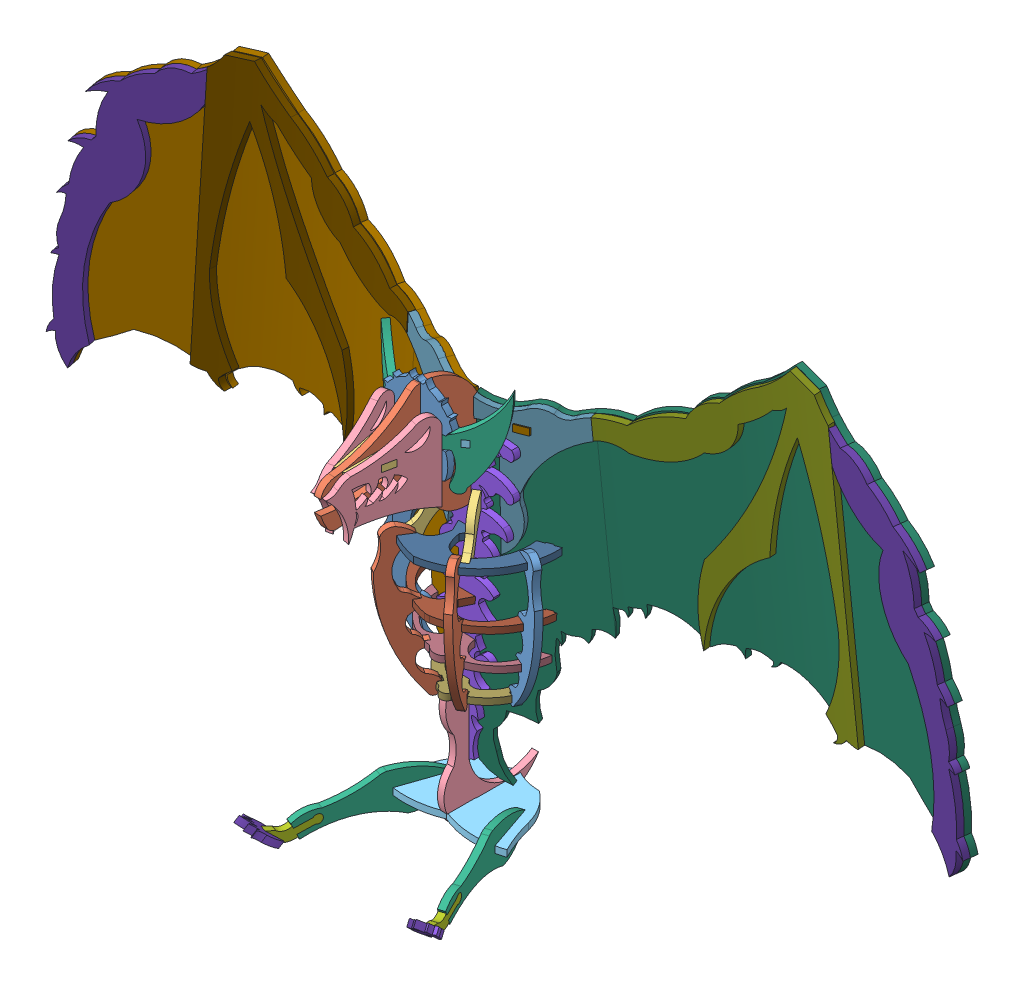
SolidWorks assembly _Assy, Bat, Flying, configuration Default. Lengths in mm.
Overall size (215.25 118.83 64.82).
41 component instances, 27 part files, 95 mates.
Components (placement in the parent):
- Bat, Face Plt-1: Bat, Face Plt [Default] at (-62.3801 20.9835 -3.9539) size (16.29 23.2 1.52)
- Bat, Face Plt, Nose-1: Bat, Face Plt, Nose [Default] at (-39.9409 20.9835 -3.9539) x (0 0 -1) z (1 0 0) size (36.38 29.99 1.52)
- Bat, Face Plt, Expander-1: Bat, Face Plt, Expander [Default] at (-39.9409 35.1614 -3.9539) x (0 0 -1) z (0 1 0) size (15.4 4.63 1.52)
- Bat, Face Plt, Teeth-1: Bat, Face Plt, Teeth [Default] at (-34.1101 35.1614 -2.7499) x (-0.202217 0 0.979341) z (0.979341 0 0.202217) size (22.91 19.58 1.52)
- Bat, Face Plt, Ear Plt-1: Bat, Face Plt, Ear Plt [Default] at (-62.3801 35.261 -3.9539) x (1 0 0) z (0 1 0) size (8.46 5.88 1.52)
- Bat, Face Plt, Ear-1: Bat, Face Plt, Ear [Default] at (-53.0588 35.261 9.3213) x (-0.818401 0 0.574647) z (0.574647 0 0.818401) size (12.49 21.12 1.52)
- Bat, Face Plt, Teeth-2: Bat, Face Plt, Teeth [Default] at (-45.7403 35.1614 -2.4417) x (0.202217 0 0.979341) z (0.979341 0 -0.202217) size (22.91 19.58 1.52)
- Bat, Face Plt, Expander-2: Bat, Face Plt, Expander [Default] at (-38.4169 36.6854 -3.9539) x (0 0 -1) z (0 -1 0) size (15.4 4.63 1.52)
- Bat, Face Plt, Ear-2: Bat, Face Plt, Ear [Default] at (-26.1748 35.261 10.5686) x (0.818401 0 0.574647) z (0.574647 0 -0.818401) size (12.49 21.12 1.52)
- MirrorBat, Face Plt, Ear Plt-2: MirrorBat, Face Plt, Ear Plt [Default] at (-15.9777 35.261 -3.9539) x (-1 0 0) z (0 -1 0) size (8.46 5.88 1.52)
- Bat, Spine, Front-1: Bat, Spine, Front [Default] at (-147.0873 -31.5779 -15.5878) x (0.998851 -0.047917 0) z (0 0 1) size (21.81 67.72 1.52)
- Bat, Wings-2: Bat, Wings [Default] at (-144.5374 -32.2165 -25.3646) x (0.986167 -0.01182 -0.165334) z (0.164778 -0.038319 0.985586) size (104.52 105.42 29.37)
- MirrorBat, Wings, Rib, top, 01-1: MirrorBat, Wings, Rib, top, 01 [Default] at (-146.7849 9.8278 -15.5878) x (0.999973 -0.007302 0) z (0.007302 0.999973 0) size (30.95 20.04 1.52)
- MirrorBat, Wings, Rib, top, 02-1: MirrorBat, Wings, Rib, top, 02 [Default] at (-146.8825 -3.5304 -15.5878) x (0.999973 -0.007302 0) z (0.007302 0.999973 0) size (29.45 16.9 1.52)
- MirrorBat, Wings, Rib, top, 03-1: MirrorBat, Wings, Rib, top, 03 [Default] at (-147.009 -20.866 -15.5878) x (0.999973 -0.007302 0) z (0.007302 0.999973 0) size (20.14 12.02 1.52)
- MirrorBat, Wings, Rib, top, 04-1: MirrorBat, Wings, Rib, top, 04 [Default] at (-146.9458 -12.1982 -15.5878) x (0.999973 -0.007302 0) z (0.007302 0.999973 0) size (28.14 15.12 1.52)
- Bat, Wings, Arm Base-1: Bat, Wings, Arm Base [Default] at (56.8928 -32.4119 -50.4796) x (0.937217 0.009342 -0.348622) z (0.348562 0.007465 0.937256) size (21.75 32.07 1.52)
- Bat, Wings, Arm Base-2: Bat, Wings, Arm Base [Default] at (-135.7818 -32.4006 -49.0512) x (-0.937217 0.009342 -0.348622) z (0.348562 -0.007465 -0.937256) size (21.75 32.07 1.52)
- MirrorBat, Wings-6: MirrorBat, Wings [Default] at (66.1796 -32.2165 -25.3646) x (-0.986167 -0.01182 -0.165334) z (0.164778 0.038319 -0.985586) size (104.52 105.42 29.37)
- Bat, Wings, Radial Arms-1: Bat, Wings, Radial Arms [Default] at (27.6708 -82.868 69.3138) x (0.348562 0.007465 0.937256) z (-0.933282 -0.089566 0.347797) size (16.34 72.23 52.54)
- MirrorBat, Wings, Arm, Outer-1: MirrorBat, Wings, Arm, Outer [Default] at (66.1796 -32.2165 -25.3646) x (0.986167 0.01182 0.165334) z (-0.164778 -0.038319 0.985586) size (33.57 74.51 1.52)
- MirrorBat, Wings, Radial Arms-2: MirrorBat, Wings, Radial Arms [Default] at (-106.0286 -82.868 69.3138) x (-0.348562 0.007465 0.937256) z (-0.933282 0.089566 -0.347797) size (18.57 72.23 53.45)
- MirrorBat, Wings, Arm, Outer-2: MirrorBat, Wings, Arm, Outer [Default] at (-144.2863 -32.2749 -23.8626) x (-0.986167 0.01182 0.165334) z (-0.164778 0.038319 -0.985586) size (33.57 74.51 1.52)
- Bat, Rib - 01-1: Bat, Rib - 01 [Default] at (-127.2159 9.6849 -60.1974) x (-0.915735 0.006687 -0.401728) z (-0.401717 0.002933 0.915759) size (11.42 35.16 1.52)
- Bat, Rib - 01-3: Bat, Rib - 01 [Default] at (49.2802 8.3961 -58.7593) x (0.915735 -0.006687 -0.401728) z (-0.401717 0.002933 -0.915759) size (11.42 35.16 1.52)
- Bat, Rib - 02-1: Bat, Rib - 02 [Default] at (-91.0947 9.4211 -99.9348) x (-0.527883 0.003855 -0.849308) z (-0.849286 0.006202 0.527897) size (11.8 35.16 1.52)
- Bat, Rib - 02-2: Bat, Rib - 02 [Default] at (13.9378 8.6542 -99.1303) x (0.527883 -0.003855 -0.849308) z (-0.849286 0.006202 -0.527897) size (11.8 35.16 1.52)
- Bat, Throat-1: Bat, Throat [Default] at (-91.0947 9.4211 -99.9348) x (0.527883 -0.003855 0.849308) z (0.849286 -0.006202 -0.527897) size (8.45 11.32 1.52)
- Bat, Throat-2: Bat, Throat [Default] at (11.4426 9.4117 -100.7393) x (-0.527883 -0.003855 0.849308) z (0.849286 0.006202 0.527897) size (8.45 11.32 1.52)
- Bat, Pelvis Suppt-1: Bat, Pelvis Suppt [Default] at (-40.3243 -32.0566 -15.5878) x (0 0 -1) z (0.99999 -0.004484 0) size (21.97 27.37 1.52)
- Bat, Pelvis-1: Bat, Pelvis [Default] at (-40.3893 -46.5653 -15.5878) x (0 0 -1) z (0.004484 0.99999 0) size (18.14 29.39 1.52)
- Bat, Thigh-01-1: Bat, Thigh-01 [Default] at (-32.1702 -46.6022 -18.4049) x (0.324228 -0.001454 0.945978) z (0.945968 -0.004242 -0.324231) size (29.77 9.67 1.52)
- Bat, Thigh-01-2: Bat, Thigh-01 [Default] at (-48.5261 -46.5288 -18.899) x (-0.324228 0.001454 0.945978) z (0.945968 -0.004242 0.324231) size (29.77 9.67 1.52)
- Bat, Ankle-1: Bat, Ankle [Default] at (-30.7285 -46.6086 -18.899) x (0.324228 -0.001454 0.945978) z (0.945968 -0.004242 -0.324231) size (10.72 3.94 1.52)
- Bat, Foot-1: Bat, Foot [Default] at (-25.8591 -63.6253 -4.4694) x (0.244285 0.66687 0.703996) z (0.213234 -0.745162 0.631874) size (10.42 5.91 1.52)
- Bat, Ankle-2: Bat, Ankle [Default] at (-47.0845 -46.5353 -18.4049) x (-0.324228 0.001454 0.945978) z (0.945968 -0.004242 0.324231) size (10.72 3.94 1.52)
- Bat, Foot-2: Bat, Foot [Default] at (-52.1064 -63.5076 -3.9753) x (-0.238295 0.669034 0.703996) z (-0.219908 -0.74322 0.631874) size (10.42 5.91 1.52)
- Bat, Tab-1: Bat, Tab [Default] at (-30.7551 18.5118 -16.4053) x (-0.348562 -0.007465 -0.937256) z (0.937217 0.009342 -0.348622) size (3.17 3.05 1.57)
- Bat, Tab-2: Bat, Tab [Default] at (-31.0167 32.2726 -16.4176) x (-0.348562 -0.007465 -0.937256) z (0.011358 -0.999929 0.00374) size (3.17 3.05 1.57)
- Bat, Tab-3: Bat, Tab [Default] at (-47.3232 33.8472 -16.4235) x (0.348562 -0.007465 -0.937256) z (0.011358 0.999929 -0.00374) size (3.17 3.05 1.57)
- Bat, Tab-4: Bat, Tab [Default] at (-46.1268 18.497 -15.8563) x (0.348562 -0.007465 -0.937256) z (0.937217 -0.009342 0.348622) size (3.17 3.05 1.57)
Mates (geometry in assembly coordinates):
- InPlace3: in place: plane of ? through (-37.7339 36.6637 18.1083) normal (0.979341 0 0.202217); plane of ? through (-32.6048 0 -6.7323) normal (0.979341 0 0.202217); moOrthogonalPlaneRef_w of ? through (-37.7339 36.6637 18.1083) normal (0.979341 0 0.202217); unknown of ?; plane of ? through (-37.7339 36.6637 18.1083) normal (0.979341 0 0.202217); plane of ? through (-32.6048 0 -6.7323) normal (0.202217 0 -0.979341); plane of Bat, Face Plt, Expander-1 through (-38.4169 36.6854 18.1083) normal (0.979341 0 0.202217); unknown of Bat, Face Plt, Teeth-1
- Coincident7: coincident aligned: plane of Bat, Face Plt, Expander-1; plane of Bat, Face Plt, Teeth-1
- Coincident8: coincident aligned: moOrthogonalPlaneRef_w of Bat, Face Plt, Expander-1 through (-34.1101 35.1614 -2.7499) normal (0 -1 0); plane of Bat, Face Plt, Teeth-1
- Coincident9: coincident anti-aligned: moOrthogonalPlaneRef_w of Bat, Face Plt, Expander-1 through (-34.1101 35.1614 -2.7499) normal (0.202217 0 -0.979341); plane of Bat, Face Plt, Teeth-1
- Coincident10: coincident anti-aligned: plane of Bat, Face Plt-1 through (-39.9409 23.2646 -2.4299) normal (1 0 0); plane of Bat, Face Plt, Nose-1 through (-39.9409 30.0921 -1.7764) normal (-1 0 0)
- Coincident11: coincident anti-aligned: plane of Bat, Face Plt-1 through (-39.9409 36.4239 -2.4299) normal (0 -1 0); plane of Bat, Face Plt, Nose-1 through (-38.4169 36.4239 -3.9539) normal (0 1 0)
- Coincident12: coincident anti-aligned: plane of Bat, Face Plt-1 through (-38.8869 25.4165 -2.4299) normal (0 0 1); plane of Bat, Face Plt, Nose-1 through (-38.4169 36.4239 -2.4299) normal (0 0 -1)
- Coincident13: coincident anti-aligned: plane of Bat, Face Plt, Nose-1 through (-38.4169 36.6854 7.0951) normal (0 0 -1); plane of Bat, Face Plt, Expander-1 through (-39.1789 36.6854 7.0951) normal (0 0 1)
- Coincident14: coincident anti-aligned: plane of Bat, Face Plt, Nose-1 through (-38.4169 30.0921 -1.7764) normal (1 0 0); plane of Bat, Face Plt, Expander-1 through (-38.4169 36.6854 7.0951) normal (-1 0 0)
- Coincident15: coincident anti-aligned: plane of Bat, Face Plt, Nose-1 through (-38.4169 36.6854 7.0951) normal (0 -1 0); plane of Bat, Face Plt, Expander-1 through (-39.9409 36.6854 -3.9539) normal (0 1 0)
- InPlace4: in place: plane of Bat, Face Plt-1 through (-34.1525 35.261 -2.4299) normal (0 1 0); plane of ? through (0 35.261 0) normal (0 1 0); plane of Bat, Face Plt-1 through (-34.1525 35.261 -2.4299) normal (0 1 0); plane of ? through (0 35.261 0) normal (0 0 -1); plane of Bat, Face Plt-1 through (-34.1525 35.261 -2.4299) normal (0 1 0); line of ? through (-55 0 35.261) axis (0 1 0); plane of Bat, Face Plt-1 through (-34.1525 35.261 -2.4299) normal (0 1 0); unknown of Bat, Face Plt, Ear Plt-1
- Coincident16: coincident aligned: plane of Bat, Face Plt-1; plane of Bat, Face Plt, Ear Plt-1
- Coincident17: coincident aligned: moOrthogonalPlaneRef_w of Bat, Face Plt-1 through (-62.3801 35.261 -3.9539) normal (0 0 -1); plane of Bat, Face Plt, Ear Plt-1 through (-62.3801 35.261 -3.9539) normal (0 0 -1)
- Coincident18: coincident anti-aligned: moOrthogonalPlaneRef_w of Bat, Face Plt-1 through (-62.3801 35.261 -3.9539) normal (-1 0 0); plane of Bat, Face Plt, Ear Plt-1
- InPlace5: in place: plane of Bat, Face Plt, Ear Plt-1 through (-34.1525 36.785 -3.9539) normal (0.574647 0 0.818401); plane of ? through (-13.1373 0 -18.7099) normal (0.574647 0 0.818401); plane of Bat, Face Plt, Ear Plt-1 through (-34.1525 36.785 -3.9539) normal (0.574647 0 0.818401); unknown of ?; plane of Bat, Face Plt, Ear Plt-1 through (-34.1525 36.785 -3.9539) normal (0.574647 0 0.818401); plane of ? through (-13.1373 0 -18.7099) normal (0.818401 0 -0.574647); plane of Bat, Face Plt, Ear Plt-1 through (-34.1525 36.785 -3.9539) normal (0.574647 0 0.818401); unknown of Bat, Face Plt, Ear-1
- Coincident19: coincident aligned: plane of Bat, Face Plt, Ear Plt-1; plane of Bat, Face Plt, Ear-1
- Coincident20: coincident aligned: moOrthogonalPlaneRef_w of Bat, Face Plt, Ear Plt-1 through (-53.0588 35.261 9.3213) normal (0 -1 0); plane of Bat, Face Plt, Ear-1
- Coincident21: coincident anti-aligned: moOrthogonalPlaneRef_w of Bat, Face Plt, Ear Plt-1 through (-53.0588 35.261 9.3213) normal (0.818401 0 -0.574647); plane of Bat, Face Plt, Ear-1
- Coincident29: coincident anti-aligned: plane of Bat, Face Plt, Nose-1 through (-39.9409 30.0921 -1.7764) normal (-1 0 0); plane of Bat, Spine, Front-1 through (-39.9409 29.4433 -14.0638) normal (1 0 0)
- Coincident30: coincident aligned: plane of Bat, Face Plt, Nose-1 through (-38.4169 37.0843 -15.5878) normal (0 0 -1); plane of Bat, Spine, Front-1 through (-31.5953 16.4503 -15.5878) normal (0 0 -1)
- Coincident38: coincident aligned: moEndPointRef_w of Bat, Face Plt, Nose-1; line of Bat, Spine, Front-1 through (-38.4169 15.4337 -15.5878) axis (-0.999973 0.007302 0)
- InPlace6: in place: plane of Bat, Spine, Front-1 through (-39.9876 9.048 -14.0638) normal (0.007302 0.999973 0); plane of ? through (0.0639 8.7555 0) normal (0.007302 0.999973 0); plane of Bat, Spine, Front-1 through (-39.9876 9.048 -14.0638) normal (0.007302 0.999973 0); unknown of ?; plane of Bat, Spine, Front-1 through (-39.9876 9.048 -14.0638) normal (0.007302 0.999973 0); unknown of ?; plane of Bat, Spine, Front-1 through (-39.9876 9.048 -14.0638) normal (0.007302 0.999973 0); unknown of MirrorBat, Wings, Rib, top, 01-1
- Coincident39: coincident aligned: plane of ?; plane of ?
- Coincident40: coincident aligned: moOrthogonalPlaneRef_w of Bat, Spine, Front-1 through (-146.7849 9.8278 -15.5878) normal (0 0 -1); plane of MirrorBat, Wings, Rib, top, 01-1
- Coincident41: coincident anti-aligned: moOrthogonalPlaneRef_w of Bat, Spine, Front-1 through (-146.7849 9.8278 -15.5878) normal (-0.999973 0.007302 0); plane of MirrorBat, Wings, Rib, top, 01-1
- InPlace7: in place: plane of Bat, Spine, Front-1 through (-40.0851 -4.3103 -14.0638) normal (0.007302 0.999973 0); plane of ? through (-0.0336 -4.6027 0) normal (0.007302 0.999973 0); plane of Bat, Spine, Front-1 through (-40.0851 -4.3103 -14.0638) normal (0.007302 0.999973 0); unknown of ?; plane of Bat, Spine, Front-1 through (-40.0851 -4.3103 -14.0638) normal (0.007302 0.999973 0); unknown of ?; plane of Bat, Spine, Front-1 through (-40.0851 -4.3103 -14.0638) normal (0.007302 0.999973 0); unknown of MirrorBat, Wings, Rib, top, 02-1
- Coincident44: coincident aligned: plane of ?; plane of ?
- Coincident45: coincident aligned: moOrthogonalPlaneRef_w of Bat, Spine, Front-1 through (-146.8825 -3.5304 -15.5878) normal (0 0 -1); plane of MirrorBat, Wings, Rib, top, 02-1
- Coincident46: coincident anti-aligned: moOrthogonalPlaneRef_w of Bat, Spine, Front-1 through (-146.8825 -3.5304 -15.5878) normal (-0.999973 0.007302 0); plane of MirrorBat, Wings, Rib, top, 02-1
- InPlace8: in place: plane of Bat, Spine, Front-1 through (-40.2117 -21.6459 -14.0638) normal (0.007302 0.999973 0); plane of ? through (-0.1602 -21.9384 0) normal (0.007302 0.999973 0); plane of Bat, Spine, Front-1 through (-40.2117 -21.6459 -14.0638) normal (0.007302 0.999973 0); unknown of ?; plane of Bat, Spine, Front-1 through (-40.2117 -21.6459 -14.0638) normal (0.007302 0.999973 0); unknown of ?; plane of Bat, Spine, Front-1 through (-40.2117 -21.6459 -14.0638) normal (0.007302 0.999973 0); unknown of MirrorBat, Wings, Rib, top, 03-1
- Coincident47: coincident aligned: plane of ?; plane of ?
- Coincident48: coincident aligned: moOrthogonalPlaneRef_w of Bat, Spine, Front-1 through (-147.009 -20.866 -15.5878) normal (0 0 -1); plane of MirrorBat, Wings, Rib, top, 03-1
- Coincident49: coincident anti-aligned: moOrthogonalPlaneRef_w of Bat, Spine, Front-1 through (-147.009 -20.866 -15.5878) normal (-0.999973 0.007302 0); plane of MirrorBat, Wings, Rib, top, 03-1
- InPlace9: in place: plane of Bat, Spine, Front-1 through (-40.1484 -12.9781 -14.0638) normal (0.007302 0.999973 0); plane of ? through (-0.0969 -13.2706 0) normal (0.007302 0.999973 0); plane of Bat, Spine, Front-1 through (-40.1484 -12.9781 -14.0638) normal (0.007302 0.999973 0); unknown of ?; plane of Bat, Spine, Front-1 through (-40.1484 -12.9781 -14.0638) normal (0.007302 0.999973 0); unknown of ?; plane of Bat, Spine, Front-1 through (-40.1484 -12.9781 -14.0638) normal (0.007302 0.999973 0); unknown of MirrorBat, Wings, Rib, top, 04-1
- Coincident50: coincident aligned: plane of ?; plane of ?
- Coincident51: coincident aligned: moOrthogonalPlaneRef_w of Bat, Spine, Front-1 through (-146.9458 -12.1982 -15.5878) normal (0 0 -1); plane of MirrorBat, Wings, Rib, top, 04-1
- Coincident52: coincident anti-aligned: moOrthogonalPlaneRef_w of Bat, Spine, Front-1 through (-146.9458 -12.1982 -15.5878) normal (-0.999973 0.007302 0); plane of MirrorBat, Wings, Rib, top, 04-1
- Concentric1: concentric aligned: cylinder of MirrorBat, Wings-6 through (10.3398 116.581 74.1706) axis (0.086543 -0.995953 -0.024253) radius 101.6; cylinder of Bat, Wings, Radial Arms-1 through (14.4816 68.9152 73.0099) axis (0.086543 -0.995953 -0.024253) radius 101.6
- Lock1: lock: unknown of Bat, Face Plt-1; unknown of Bat, Wings-2
- InPlace10: in place: plane of MirrorBat, Wings-6 through (-26.9951 -32.3521 -40.9475) normal (-0.164778 -0.038319 0.985586); plane of ? through (5.7127 1.3285 -34.1697) normal (-0.164778 -0.038319 0.985586); plane of MirrorBat, Wings-6 through (-26.9951 -32.3521 -40.9475) normal (-0.164778 -0.038319 0.985586); unknown of ?; plane of MirrorBat, Wings-6 through (-26.9951 -32.3521 -40.9475) normal (-0.164778 -0.038319 0.985586); unknown of ?; plane of MirrorBat, Wings-6 through (-26.9951 -32.3521 -40.9475) normal (-0.164778 -0.038319 0.985586); unknown of MirrorBat, Wings, Arm, Outer-1
- Coincident40: coincident aligned: plane of ?; plane of ?
- Coincident41: coincident aligned: moOrthogonalPlaneRef_w of MirrorBat, Wings-6 through (66.1796 -32.2165 -25.3646) normal (-0.017985 0.999196 0.035841); plane of MirrorBat, Wings, Arm, Outer-1
- Coincident42: coincident anti-aligned: moOrthogonalPlaneRef_w of MirrorBat, Wings-6 through (66.1796 -32.2165 -25.3646) normal (-0.986167 -0.01182 -0.165334); plane of MirrorBat, Wings, Arm, Outer-1
- InPlace11: in place: plane of MirrorBat, Wings, Rib, top, 01-1 through (-127.2048 11.2089 -60.1974) normal (-0.401717 0.002933 0.915759); plane of ? through (1.6041 -0.0117 -3.6567) normal (-0.401717 0.002933 0.915759); plane of MirrorBat, Wings, Rib, top, 01-1 through (-127.2048 11.2089 -60.1974) normal (-0.401717 0.002933 0.915759); unknown of ?; plane of MirrorBat, Wings, Rib, top, 01-1 through (-127.2048 11.2089 -60.1974) normal (-0.401717 0.002933 0.915759); unknown of ?; plane of MirrorBat, Wings, Rib, top, 01-1 through (-127.2048 11.2089 -60.1974) normal (-0.401717 0.002933 0.915759); unknown of Bat, Rib - 01-1
- Coincident43: coincident aligned: plane of ?; plane of ?
- Coincident44: coincident aligned: moOrthogonalPlaneRef_w of MirrorBat, Wings, Rib, top, 01-1 through (-127.2159 9.6849 -60.1974) normal (-0.007302 -0.999973 0); plane of Bat, Rib - 01-1
- Coincident45: coincident anti-aligned: moOrthogonalPlaneRef_w of MirrorBat, Wings, Rib, top, 01-1 through (-127.2159 9.6849 -60.1974) normal (0.915735 -0.006687 0.401728); plane of Bat, Rib - 01-1
- Coincident49: coincident anti-aligned: plane of MirrorBat, Wings, Rib, top, 01-1 through (-131.6257 11.2412 18.9439) normal (0.401717 -0.002933 0.915759); plane of Bat, Rib - 01-3 through (48.668 8.4006 -60.155) normal (-0.401717 0.002933 -0.915759)
- Coincident53: coincident anti-aligned: plane of MirrorBat, Wings, Rib, top, 01-1 through (-146.7738 11.3518 -15.5878) normal (0.007302 0.999973 0); plane of Bat, Rib - 01-3 through (48.6791 9.9245 -60.155) normal (-0.007302 -0.999973 0)
- Coincident54: coincident: moEndPointRef_w of MirrorBat, Wings, Rib, top, 01-1; plane of Bat, Rib - 01-3 through (-52.8177 9.1416 -15.6337) normal (0.915735 -0.006687 -0.401728)
- Coincident56: coincident anti-aligned: plane of MirrorBat, Wings, Rib, top, 01-1 through (-146.7738 11.3518 -15.5878) normal (0.007302 0.999973 0); plane of Bat, Rib - 02-1 through (-92.3779 10.9546 -99.1303) normal (-0.007302 -0.999973 0)
- Coincident57: coincident anti-aligned: plane of MirrorBat, Wings, Rib, top, 01-1 through (-68.7873 10.7823 -64.0625) normal (-0.849286 0.006202 0.527897); plane of Bat, Rib - 02-1 through (-91.0947 9.4211 -99.9348) normal (0.849286 -0.006202 -0.527897)
- Coincident58: coincident: moEndPointRef_w of MirrorBat, Wings, Rib, top, 01-1; plane of Bat, Rib - 02-1 through (-33.8867 9.0034 -5.0062) normal (-0.527883 0.003855 -0.849308)
- Coincident59: coincident anti-aligned: plane of MirrorBat, Wings, Rib, top, 01-1 through (-69.5899 10.7882 32.388) normal (0.849286 -0.006202 0.527897); plane of Bat, Rib - 02-2 through (12.6435 8.6636 -99.9348) normal (-0.849286 0.006202 -0.527897)
- Coincident60: coincident anti-aligned: plane of MirrorBat, Wings, Rib, top, 01-1 through (-146.7738 11.3518 -15.5878) normal (0.007302 0.999973 0); plane of Bat, Rib - 02-2 through (12.6546 10.1876 -99.9348) normal (-0.007302 -0.999973 0)
- Coincident61: coincident: moEndPointRef_w of MirrorBat, Wings, Rib, top, 01-1; plane of Bat, Rib - 02-2 through (-45.8588 9.0908 -5.8108) normal (0.527883 -0.003855 -0.849308)
- InPlace12: in place: plane of Bat, Rib - 02-1 through (-91.0947 9.4211 -99.9348) normal (0.849286 -0.006202 -0.527897); plane of ? through (-20.9507 0.153 13.0225) normal (0.849286 -0.006202 -0.527897); plane of Bat, Rib - 02-1 through (-91.0947 9.4211 -99.9348) normal (0.849286 -0.006202 -0.527897); unknown of ?; plane of Bat, Rib - 02-1 through (-91.0947 9.4211 -99.9348) normal (0.849286 -0.006202 -0.527897); unknown of ?; plane of Bat, Rib - 02-1 through (-91.0947 9.4211 -99.9348) normal (0.849286 -0.006202 -0.527897); unknown of Bat, Throat-1
- Coincident62: coincident aligned: plane of ?; plane of ?
- Coincident63: coincident aligned: moOrthogonalPlaneRef_w of Bat, Rib - 02-1 through (-91.0947 9.4211 -99.9348) normal (-0.007302 -0.999973 0); plane of Bat, Throat-1
- Coincident64: coincident anti-aligned: moOrthogonalPlaneRef_w of Bat, Rib - 02-1 through (-91.0947 9.4211 -99.9348) normal (-0.527883 0.003855 -0.849308); plane of Bat, Throat-1
- InPlace13: in place: plane of Bat, Spine, Front-1 through (-40.3167 -30.3569 -15.5878) normal (0.99999 -0.004484 0); plane of ? through (-40.1797 0.1802 0) normal (0.99999 -0.004484 0); plane of Bat, Spine, Front-1 through (-40.3167 -30.3569 -15.5878) normal (0.99999 -0.004484 0); line of ? through (-55 -40.1797 0.1802) axis (0 0.004484 0.99999); plane of Bat, Spine, Front-1 through (-40.3167 -30.3569 -15.5878) normal (0.99999 -0.004484 0); unknown of ?; plane of Bat, Spine, Front-1 through (-40.3167 -30.3569 -15.5878) normal (0.99999 -0.004484 0); unknown of Bat, Pelvis Suppt-1
- Coincident65: coincident aligned: plane of ?; plane of ?
- Coincident66: coincident aligned: moOrthogonalPlaneRef_w of Bat, Spine, Front-1 through (-40.3243 -32.0566 -15.5878) normal (0.004484 0.99999 0); plane of Bat, Pelvis Suppt-1
- Coincident67: coincident anti-aligned: moOrthogonalPlaneRef_w of Bat, Spine, Front-1 through (-40.3243 -32.0566 -15.5878) normal (0 0 1); plane of Bat, Pelvis Suppt-1
- InPlace14: in place: plane of Bat, Pelvis Suppt-1 through (-38.8654 -46.5721 -15.8732) normal (0.004484 0.99999 0); plane of ? through (-0.2096 -46.7455 0) normal (0.004484 0.99999 0); plane of Bat, Pelvis Suppt-1 through (-38.8654 -46.5721 -15.8732) normal (0.004484 0.99999 0); unknown of ?; plane of Bat, Pelvis Suppt-1 through (-38.8654 -46.5721 -15.8732) normal (0.004484 0.99999 0); unknown of ?; plane of Bat, Pelvis Suppt-1 through (-38.8654 -46.5721 -15.8732) normal (0.004484 0.99999 0); unknown of Bat, Pelvis-1
- Coincident68: coincident aligned: plane of ?; plane of ?
- Coincident69: coincident aligned: moOrthogonalPlaneRef_w of Bat, Pelvis Suppt-1 through (-40.3893 -46.5653 -15.5878) normal (-0.99999 0.004484 0); plane of Bat, Pelvis-1
- Coincident70: coincident anti-aligned: moOrthogonalPlaneRef_w of Bat, Pelvis Suppt-1 through (-40.3893 -46.5653 -15.5878) normal (0 0 1); plane of Bat, Pelvis-1
- InPlace16: in place: plane of Bat, Pelvis-1 through (-28.6498 -45.0939 -8.1537) normal (0.945968 -0.004242 -0.324231); plane of ? through (-22.9557 0.1029 7.8681) normal (0.945968 -0.004242 -0.324231); plane of Bat, Pelvis-1 through (-28.6498 -45.0939 -8.1537) normal (0.945968 -0.004242 -0.324231); unknown of ?; plane of Bat, Pelvis-1 through (-28.6498 -45.0939 -8.1537) normal (0.945968 -0.004242 -0.324231); unknown of ?; plane of Bat, Pelvis-1 through (-28.6498 -45.0939 -8.1537) normal (0.945968 -0.004242 -0.324231); unknown of Bat, Thigh-01-1
- Coincident76: coincident aligned: plane of ?; plane of ?
- Coincident77: coincident aligned: moOrthogonalPlaneRef_w of Bat, Pelvis-1 through (-32.1702 -46.6022 -18.4049) normal (-0.004484 -0.99999 0); plane of Bat, Thigh-01-1
- Coincident78: coincident anti-aligned: moOrthogonalPlaneRef_w of Bat, Pelvis-1 through (-32.1702 -46.6022 -18.4049) normal (-0.324228 0.001454 -0.945978); plane of Bat, Thigh-01-1
- Coincident79: coincident anti-aligned: plane of Bat, Pelvis-1 through (-52.11 -44.9887 -8.4226) normal (0.945968 -0.004242 0.324231); plane of Bat, Thigh-01-2 through (-50.809 -42.7584 -12.1894) normal (-0.945968 0.004242 -0.324231)
- Coincident80: coincident anti-aligned: plane of Bat, Pelvis-1 through (-46.2246 -45.0151 -36.8552) normal (0.004484 0.99999 0); plane of Bat, Thigh-01-2 through (-48.4914 -45.005 -14.2801) normal (-0.004484 -0.99999 0)
- Coincident81: coincident anti-aligned: plane of Bat, Pelvis-1 through (-49.9331 -44.9985 -14.7743) normal (-0.324228 0.001454 0.945978); plane of Bat, Thigh-01-2 through (-48.4982 -46.5289 -14.2801) normal (0.324228 -0.001454 -0.945978)
- InPlace17: in place: plane of Bat, Thigh-01-1 through (-28.412 -42.8588 -12.1894) normal (0.945968 -0.004242 -0.324231); plane of ? through (-21.514 0.0965 7.3739) normal (0.945968 -0.004242 -0.324231); plane of Bat, Thigh-01-1 through (-28.412 -42.8588 -12.1894) normal (0.945968 -0.004242 -0.324231); unknown of ?; plane of Bat, Thigh-01-1 through (-28.412 -42.8588 -12.1894) normal (0.945968 -0.004242 -0.324231); unknown of ?; plane of Bat, Thigh-01-1 through (-28.412 -42.8588 -12.1894) normal (0.945968 -0.004242 -0.324231); unknown of Bat, Ankle-1
- Coincident82: coincident aligned: plane of ?; plane of ?
- Coincident83: coincident aligned: moOrthogonalPlaneRef_w of Bat, Thigh-01-1 through (-30.7285 -46.6086 -18.899) normal (-0.004484 -0.99999 0); plane of Bat, Ankle-1
- Coincident84: coincident anti-aligned: moOrthogonalPlaneRef_w of Bat, Thigh-01-1 through (-30.7285 -46.6086 -18.899) normal (-0.324228 0.001454 -0.945978); plane of Bat, Ankle-1
- InPlace18: in place: plane of Bat, Ankle-1 through (-21.5112 -47.8142 12.7092) normal (0.213234 -0.745162 0.631874); plane of ? through (8.3317 -29.1158 24.6892) normal (0.213234 -0.745162 0.631874); plane of Bat, Ankle-1 through (-21.5112 -47.8142 12.7092) normal (0.213234 -0.745162 0.631874); unknown of ?; plane of Bat, Ankle-1 through (-21.5112 -47.8142 12.7092) normal (0.213234 -0.745162 0.631874); unknown of ?; plane of Bat, Ankle-1 through (-21.5112 -47.8142 12.7092) normal (0.213234 -0.745162 0.631874); unknown of Bat, Foot-1
- Coincident85: coincident aligned: plane of ?; plane of ?
- Coincident86: coincident aligned: moOrthogonalPlaneRef_w of Bat, Ankle-1 through (-25.8591 -63.6253 -4.4694) normal (-0.945968 0.004242 0.324231); plane of Bat, Foot-1
- Coincident87: coincident anti-aligned: moOrthogonalPlaneRef_w of Bat, Ankle-1 through (-25.8591 -63.6253 -4.4694) normal (-0.244285 -0.66687 -0.703996); plane of Bat, Foot-1
- Coincident88: coincident anti-aligned: plane of Bat, Thigh-01-2 through (-56.5011 -47.555 9.0555) normal (0.088204 -0.958844 -0.269886); plane of Bat, Ankle-2 through (-57.9428 -47.5486 8.5614) normal (-0.088204 0.958844 0.269886)
- Coincident89: coincident aligned: plane of Bat, Thigh-01-2 through (-50.809 -42.7584 -12.1894) normal (-0.945968 0.004242 -0.324231); plane of Bat, Ankle-2 through (-56.497 -47.0249 4.35) normal (-0.945968 0.004242 -0.324231)
- Concentric2: concentric anti-aligned: cylinder of Bat, Thigh-01-2 through (-55.0553 -47.0314 4.8441) axis (-0.945968 0.004242 -0.324231) radius 1.0263; cylinder of Bat, Ankle-2 through (-56.497 -47.0249 4.35) axis (0.945968 -0.004242 0.324231) radius 1.0263
- Coincident90: coincident anti-aligned: plane of Bat, Ankle-2 through (-59.1955 -47.6452 12.2151) normal (-0.219908 -0.74322 0.631874); plane of Bat, Foot-2 through (-67.7926 -45.2836 12.0009) normal (0.219908 0.74322 -0.631874)
- Coincident91: coincident anti-aligned: plane of Bat, Ankle-2 through (-55.0553 -47.0314 4.8441) normal (0.945968 -0.004242 0.324231); plane of Bat, Foot-2 through (-58.089 -48.7844 13.6722) normal (-0.945968 0.004242 -0.324231)
- Coincident92: coincident anti-aligned: plane of Bat, Ankle-2 through (-59.4098 -48.3692 12.8306) normal (-0.238295 0.669034 0.703996); plane of Bat, Foot-2 through (-59.5307 -48.7779 13.1781) normal (0.238295 -0.669034 -0.703996)
- Coincident93: coincident anti-aligned: plane of MirrorBat, Wings-6 through (-33.3738 21.6481 -18.844) normal (0.937217 0.009342 -0.348622); plane of Bat, Tab-1 through (-32.2657 21.5448 -15.8677) normal (-0.937217 -0.009342 0.348622)
- Coincident94: coincident aligned: plane of MirrorBat, Wings-6 through (-26.3917 -32.7852 -21.0071) normal (-0.348562 -0.007465 -0.937256); plane of Bat, Tab-1 through (-31.8964 21.5358 -19.3925) normal (-0.348562 -0.007465 -0.937256)
- Coincident95: coincident anti-aligned: plane of MirrorBat, Wings-6 through (-33.3377 18.4733 -18.8321) normal (-0.011358 0.999929 -0.00374); plane of Bat, Tab-1 through (-30.7551 18.5118 -16.4053) normal (0.011358 -0.999929 0.00374)
- Coincident96: coincident aligned: plane of MirrorBat, Wings-6 through (-26.3917 -32.7852 -21.0071) normal (-0.348562 -0.007465 -0.937256); plane of Bat, Tab-2 through (-29.2667 32.2773 -20.456) normal (-0.348562 -0.007465 -0.937256)
- Coincident97: coincident anti-aligned: plane of MirrorBat, Wings-6 through (-32.1234 32.2489 -19.3934) normal (-0.011358 0.999929 -0.00374); plane of Bat, Tab-2 through (-28.1601 32.301 -17.4802) normal (0.011358 -0.999929 0.00374)
- Coincident98: coincident anti-aligned: plane of MirrorBat, Wings-6 through (-32.1414 33.8362 -19.3994) normal (0.937217 0.009342 -0.348622); plane of Bat, Tab-2 through (-31.0167 32.2726 -16.4176) normal (-0.937217 -0.009342 0.348622)
